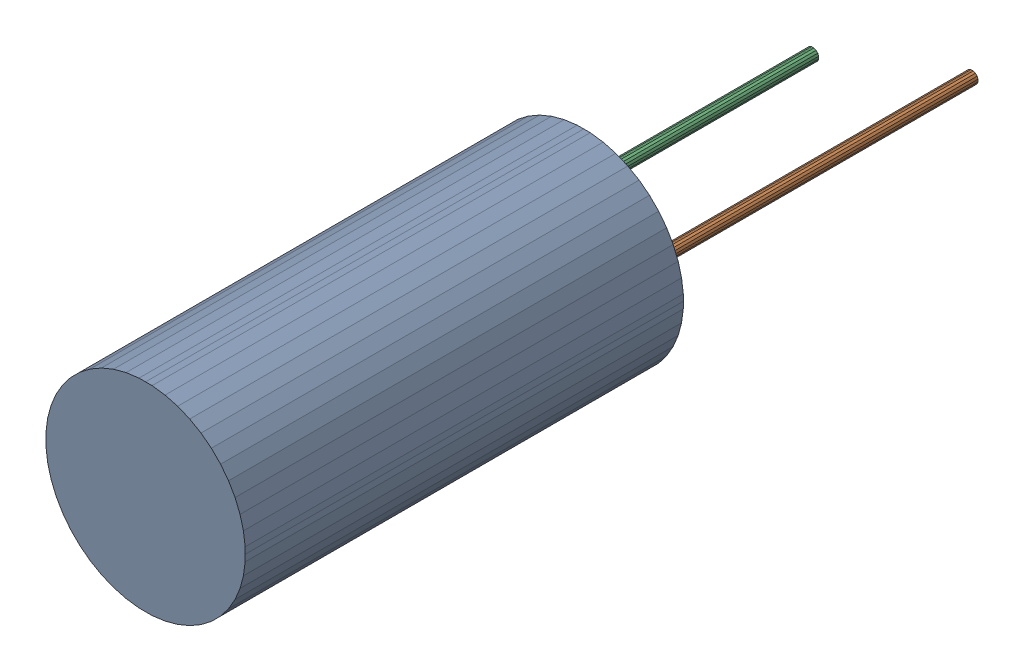
SolidWorks assembly C3.step, configuration Default. Lengths in mm.
Overall size (10 10 39).
6 component instances, 3 part files, 0 mates.
Components (placement in the parent):
- 6100340144.step-1: 6100340144.step [Default] at (123.698 53.086 0) size (10 10 22)
  - Extruded-50.step-1: Extruded-50.step [Default] at origin size (10 10 22)
- 6100332544.step-1: 6100332544.step [Default] at (126.198 53.086 -17) size (0.6 0.6 17)
  - Extruded-51.step-1: Extruded-51.step [Default] at origin size (0.6 0.6 17)
- 6100341584.step-1: 6100341584.step [Default] at (121.1981 53.0859 -14) size (0.6 0.6 14)
  - Extruded-52.step-1: Extruded-52.step [Default] at origin size (0.6 0.6 14)
